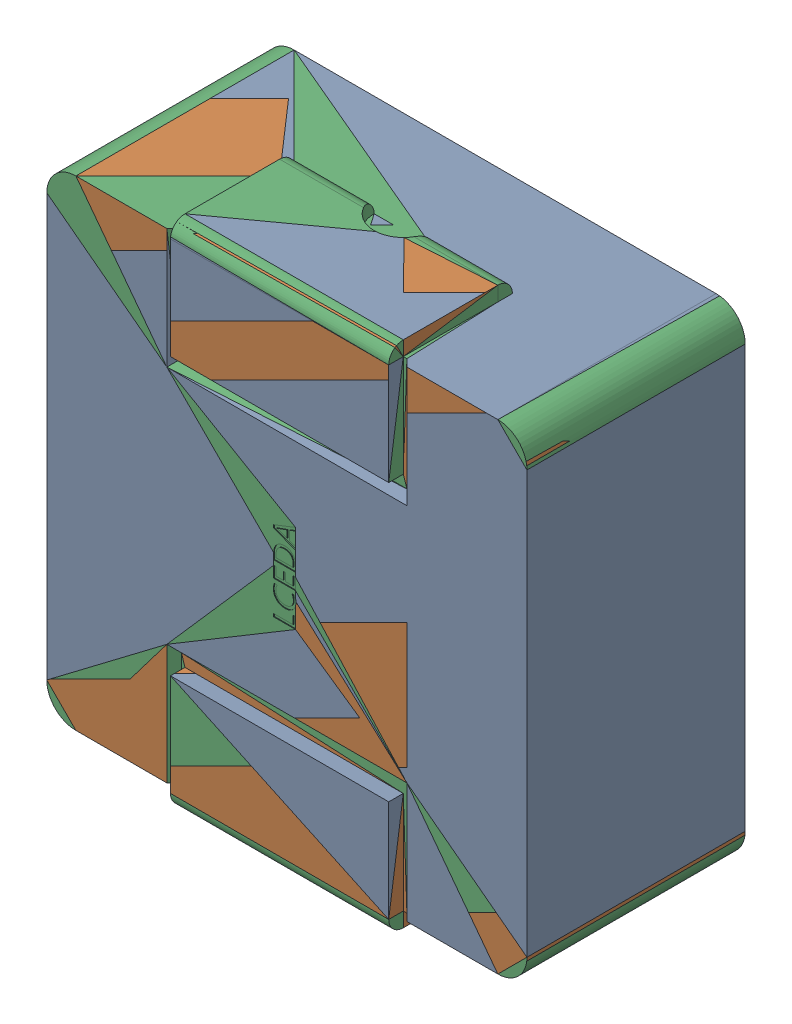
SolidWorks assembly L22, configuration Défaut. Lengths in mm.
Overall size (6.6 7.01 3.1).
3 component instances, 2 part files, 0 mates.
Components (placement in the parent):
- L7x6.8-1: L7x6.8 [Défaut] at (-1.8 -7.9313 -0.4818) x (0 -1 0) z (0 0 -1) size (7.01 6.6 3.1)
- L7x6.8-2: L7x6.8 [Défaut] at (-1.8 -7.9313 -0.4818) x (0 -1 0) z (0 0 -1) size (7.01 6.6 3.1)
- L7x6.8_1101-1: L7x6.8_1101 [Défaut] at (-1.8 -7.9313 -0.4818) x (0 -1 0) z (0 0 -1) size (7.01 6.6 3.1)
